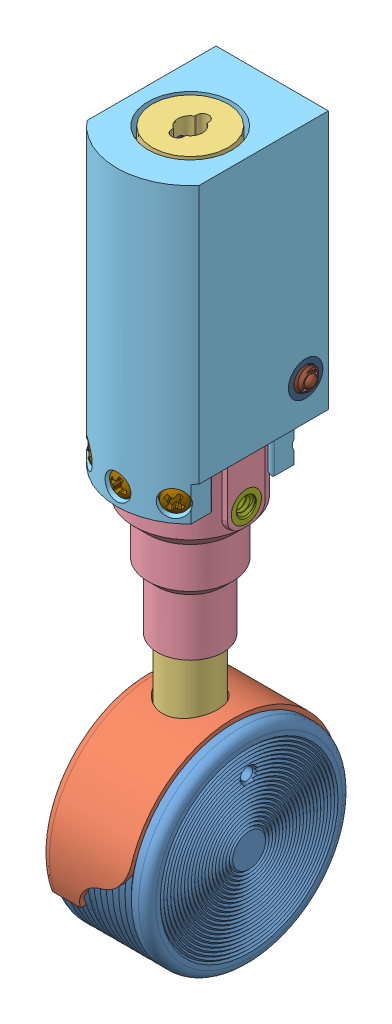
SolidWorks assembly Landing Gear Lever, configuration Default. Lengths in mm.
Overall size (23.88 129.03 39.18).
31 component instances, 15 part files, 46 mates.
Components (placement in the parent):
- Landing Gear Level Lollipop-1: Landing Gear Level Lollipop [Default] at origin size (18.84 37.59 37.59)
- Landing Gear Level Lollipop Cover-1: Landing Gear Level Lollipop Cover [Default] at origin size (15.98 27.07 39.18)
- Landing Gear Lever Shaft-1: Landing Gear Lever Shaft [Default] at (0 -43.4975 0) x (1 0 0) z (0 1 0) size (13.97 13.97 104.68)
- Landing Gear Lever Collar-1: Landing Gear Lever Collar [Default] at (0 19.05 0) x (1 0 0) z (0 1 0) size (20.7 20.7 33.34)
- Landing Gear Lever Track-1: Landing Gear Lever Track [Default] at (0 66.7385 0) x (1 0 0) z (0 1 0) size (20.7 28.64 54.09)
- 93365A110_BRASS HEAT-SET INSERT FOR PLASTICS_2-56-1: 93365A110_BRASS HEAT-SET INSERT FOR PLASTICS_2-56 [Default] at (52.1214 15.875 36.9487) x (0.77218 0.298318 -0.561021) z (0.241345 -0.954466 -0.175347) size (3.58 3.09 3.58)
- 93365A110_BRASS HEAT-SET INSERT FOR PLASTICS_2-56-2: 93365A110_BRASS HEAT-SET INSERT FOR PLASTICS_2-56 [Default] at (52.1214 15.875 20.2013) x (-0.77218 0.298318 -0.561021) z (-0.241345 -0.954466 -0.175347) size (3.58 3.09 3.58)
- 93365A110_BRASS HEAT-SET INSERT FOR PLASTICS_2-56-3: 93365A110_BRASS HEAT-SET INSERT FOR PLASTICS_2-56 [Default] at (46.0375 15.875 18.2245) x (-0.954466 0.298318 0) z (-0.298318 -0.954466 0) size (3.58 3.09 3.58)
- 93365A110_BRASS HEAT-SET INSERT FOR PLASTICS_2-56-4: 93365A110_BRASS HEAT-SET INSERT FOR PLASTICS_2-56 [Default] at (39.9536 15.875 20.2013) x (-0.77218 0.298318 0.561021) z (-0.241345 -0.954466 0.175347) size (3.58 3.09 3.58)
- 93365A110_BRASS HEAT-SET INSERT FOR PLASTICS_2-56-5: 93365A110_BRASS HEAT-SET INSERT FOR PLASTICS_2-56 [Default] at (39.9536 15.875 36.9487) x (0.77218 0.298318 0.561021) z (0.241345 -0.954466 0.175347) size (3.58 3.09 3.58)
- 93365A130 - INSERT, 6-32, BRASS, FOR PLASTICS-1: 93365A130 - INSERT, 6-32, BRASS, FOR PLASTICS [93365A130] at (35.687 11.1125 28.575) x (0 -0.259173 -0.965831) z (0 0.965831 -0.259173) size (5.56 4.29 5.56)
- 93365A130 - INSERT, 6-32, BRASS, FOR PLASTICS-2: 93365A130 - INSERT, 6-32, BRASS, FOR PLASTICS [93365A130] at (56.388 11.1125 28.575) x (0 0.666184 -0.745788) z (0 -0.745788 -0.666184) size (5.56 4.29 5.56)
- 2467A322 - PLUNGER, BALL, LONG-NOSE, 6-32-1: 2467A322 - PLUNGER, BALL, LONG-NOSE, 6-32 [2467A322] at (45.7962 61.976 28.575) x (0 -0.883555 -0.468328) z (0 0.468328 -0.883555) size (3.6 15.47 3.52)
- 93365A130 - INSERT, 6-32, BRASS, FOR PLASTICS-3: 93365A130 - INSERT, 6-32, BRASS, FOR PLASTICS [93365A130] at (39.0525 61.976 28.575) x (0 -0.827711 0.561154) z (0 -0.561154 -0.827711) size (5.56 4.29 5.56)
- 93365A130 - INSERT, 6-32, BRASS, FOR PLASTICS-4: 93365A130 - INSERT, 6-32, BRASS, FOR PLASTICS [93365A130] at (53.0225 61.976 28.575) x (0 0.992137 -0.125155) z (0 -0.125155 -0.992137) size (5.56 4.29 5.56)
- 93365A110_BRASS HEAT-SET INSERT FOR PLASTICS_2-56-6: 93365A110_BRASS HEAT-SET INSERT FOR PLASTICS_2-56 [Default] at (46.0375 15.875 38.9255) x (0.954466 0.298318 0) z (0.298318 -0.954466 0) size (3.58 3.09 3.58)
- 90272A077_ZINC-PLTD STL PAN HEAD PHILLIPS MACHINE SCREW_2-56 X .250-1: 90272A077_ZINC-PLTD STL PAN HEAD PHILLIPS MACHINE SCREW_2-56 X .250 [90272A077] at (49.3295 15.875 33.1061) x (0.466762 0.81678 -0.339122) z (0.587785 0 0.809017) size (4.24 4.24 7.94)
- 90272A077_ZINC-PLTD STL PAN HEAD PHILLIPS MACHINE SCREW_2-56 X .250-2: 90272A077_ZINC-PLTD STL PAN HEAD PHILLIPS MACHINE SCREW_2-56 X .250 [90272A077] at (42.7455 15.875 33.1061) x (0.639533 0.612454 0.464648) z (-0.587785 0 0.809017) size (4.24 4.24 7.94)
- 90272A077_ZINC-PLTD STL PAN HEAD PHILLIPS MACHINE SCREW_2-56 X .250-3: 90272A077_ZINC-PLTD STL PAN HEAD PHILLIPS MACHINE SCREW_2-56 X .250 [90272A077] at (42.7455 15.875 24.0439) x (-0.331042 -0.912449 0.240516) z (-0.587785 0 -0.809017) size (4.24 4.24 7.94)
- 90272A077_ZINC-PLTD STL PAN HEAD PHILLIPS MACHINE SCREW_2-56 X .250-4: 90272A077_ZINC-PLTD STL PAN HEAD PHILLIPS MACHINE SCREW_2-56 X .250 [90272A077] at (49.3295 15.875 24.0439) x (-0.765783 0.322529 -0.556374) z (0.587785 0 -0.809017) size (4.24 4.24 7.94)
- 90272A077_ZINC-PLTD STL PAN HEAD PHILLIPS MACHINE SCREW_2-56 X .250-5: 90272A077_ZINC-PLTD STL PAN HEAD PHILLIPS MACHINE SCREW_2-56 X .250 [90272A077] at (46.0375 15.875 34.1757) x (0.942667 -0.333735 0) z (0 0 1) size (4.24 4.24 7.94)
- 90272A077_ZINC-PLTD STL PAN HEAD PHILLIPS MACHINE SCREW_2-56 X .250-6: 90272A077_ZINC-PLTD STL PAN HEAD PHILLIPS MACHINE SCREW_2-56 X .250 [90272A077] at (46.0375 15.875 22.9743) x (-0.742719 0.669603 0) z (0 0 -1) size (4.24 4.24 7.94)
- 93365A140 - INSERT, 8-32, BRASS, FOR PLASTICS-1: 93365A140 - INSERT, 8-32, BRASS, FOR PLASTICS [93365A140] at (35.687 26.0985 17.653) x (0 0.988882 0.148702) z (0 -0.148702 0.988882) size (6.35 5.19 6.35)
- 93365A140 - INSERT, 8-32, BRASS, FOR PLASTICS-2: 93365A140 - INSERT, 8-32, BRASS, FOR PLASTICS [93365A140] at (56.388 26.0985 17.653) x (0 -0.894531 0.447005) z (0 0.447005 0.894531) size (6.35 5.19 6.35)
- 5901A122 - PLUNGER, SPRING, BALL-NOSE, 8-32 HEX DRIVE-1: 5901A122 - PLUNGER, SPRING, BALL-NOSE, 8-32 HEX DRIVE [5901A122] at (40.386 26.0985 17.653) x (0 0.998408 0.0564) z (0 -0.0564 0.998408) size (4.28 12.3 4.19)
- 5901A122 - PLUNGER, SPRING, BALL-NOSE, 8-32 HEX DRIVE-2: 5901A122 - PLUNGER, SPRING, BALL-NOSE, 8-32 HEX DRIVE [5901A122] at (51.689 26.0985 17.653) x (0 0.60561 -0.795762) z (0 -0.795762 -0.60561) size (4.28 12.3 4.19)
- 93365A102__BRASS HEAT-SET INSERT FOR PLASTICS_0-80-1: 93365A102__BRASS HEAT-SET INSERT FOR PLASTICS_0-80 [Default] at (56.388 63.5635 22.9461) x (0 -0.924225 0.381849) z (0 0.381849 0.924225) size (3.58 3.01 3.58)
- 93365A102__BRASS HEAT-SET INSERT FOR PLASTICS_0-80-2: 93365A102__BRASS HEAT-SET INSERT FOR PLASTICS_0-80 [Default] at (56.388 63.5635 16.4211) x (0 -0.85199 0.523557) z (0 0.523557 0.85199) size (3.58 3.01 3.58)
- 92671A115 - NUT, HEX, 0-80, BRASS-1: 92671A115 - NUT, HEX, 0-80, BRASS [92671A115] at (38.2984 -31.5595 28.575) x (0 -0.5 -0.866025) z (0 -0.866025 0.5) size (3.97 1.51 4.58)
- 91771A071 - FHS, 82DEG, 0-80 X .750, 18-8-1: 91771A071 - FHS, 82DEG, 0-80 X .750, 18-8 [91771A071] at (55.3967 -31.5595 28.575) x (0 0.140431 -0.99009) z (1 0 0) size (2.84 2.84 19.26)
- TLVH4200 - LED, 3mm, RED, 2.4V, 15mA, 170 DEG VIEW ANGLE, FOR BACKLIGHTING-1: TLVH4200 - LED, 3mm, RED, 2.4V, 15mA, 170 DEG VIEW ANGLE, FOR BACKLIGHTING [Default] at (46.0375 -36.1635 28.575) x (1 0 0) z (0 0 -1) size (3.33 7.5 3.5)
Mates (geometry in assembly coordinates):
- Concentric27: concentric aligned: cylinder of Landing Gear Level Lollipop-1 through (46.0375 -43.4975 28.575) axis (-1 0 0) radius 18.0023; cylinder of Landing Gear Level Lollipop Cover-1 through (46.0375 -43.4975 28.575) axis (-1 0 0) radius 18.0023
- Concentric28: concentric aligned: cylinder of Landing Gear Level Lollipop-1 through (46.0375 -28.8925 28.575) axis (0 -1 0) radius 5.08; cylinder of Landing Gear Level Lollipop Cover-1 through (46.0375 -28.8925 28.575) axis (0 -1 0) radius 5.08
- Concentric71: concentric: cone of Landing Gear Lever Collar-1 through (35.687 11.1125 28.575) axis (1 0 0); cylinder of 93365A130 - INSERT, 6-32, BRASS, FOR PLASTICS-1 through (35.687 11.1125 28.575) axis (-1 0 0) radius 2.5273
- Coincident89: coincident: plane of Landing Gear Lever Collar-1 through (35.687 19.05 0) normal (-1 0 0); plane of 93365A130 - INSERT, 6-32, BRASS, FOR PLASTICS-1 through (35.687 11.1125 28.575) normal (-1 0 0)
- Concentric70: concentric: cone of Landing Gear Lever Collar-1 through (56.388 11.1125 28.575) axis (-1 0 0); cylinder of 93365A130 - INSERT, 6-32, BRASS, FOR PLASTICS-2 through (56.388 11.1125 28.575) axis (1 0 0) radius 2.5273
- Coincident88: coincident: plane of Landing Gear Lever Collar-1 through (56.388 19.05 0) normal (1 0 0); plane of 93365A130 - INSERT, 6-32, BRASS, FOR PLASTICS-2 through (56.388 11.1125 28.575) normal (1 0 0)
- Concentric34: concentric aligned: cylinder of 2467A322 - PLUNGER, BALL, LONG-NOSE, 6-32-1 through (37.4523 61.976 28.575) axis (-1 0 0) radius 0.5715; circle of 93365A130 - INSERT, 6-32, BRASS, FOR PLASTICS-3
- Tangent15: tangent aligned: cylinder of Landing Gear Lever Shaft-1 through (46.0375 57.2135 28.575) axis (0 1 0) radius 6.985; plane of 2467A322 - PLUNGER, BALL, LONG-NOSE, 6-32-1 through (39.0525 61.976 28.575) normal (-1 0 0)
- Concentric68: concentric aligned: cylinder of Landing Gear Lever Shaft-1 through (42.8625 61.976 28.575) axis (-1 0 0) radius 1.8986; cylinder of 93365A130 - INSERT, 6-32, BRASS, FOR PLASTICS-3 through (39.0525 61.976 28.575) axis (-1 0 0) radius 2.5273
- Tangent13: tangent aligned: cylinder of Landing Gear Lever Shaft-1 through (46.0375 57.2135 28.575) axis (0 1 0) radius 6.985; plane of 93365A130 - INSERT, 6-32, BRASS, FOR PLASTICS-3 through (39.0525 61.976 28.575) normal (-1 0 0)
- Concentric69: concentric anti-aligned: cone of Landing Gear Lever Shaft-1 through (53.0225 61.976 28.575) axis (-1 0 0); cylinder of 93365A130 - INSERT, 6-32, BRASS, FOR PLASTICS-4 through (53.0225 61.976 28.575) axis (1 0 0) radius 2.5273
- Tangent14: tangent aligned: cylinder of Landing Gear Lever Shaft-1 through (46.0375 57.2135 28.575) axis (0 1 0) radius 6.985; plane of 93365A130 - INSERT, 6-32, BRASS, FOR PLASTICS-4 through (53.0225 61.976 28.575) normal (1 0 0)
- Concentric72: concentric aligned: cone of Landing Gear Lever Collar-1 through (46.0375 15.875 38.9255) axis (0 0 -1); cone of 93365A110_BRASS HEAT-SET INSERT FOR PLASTICS_2-56-6 through (46.0375 15.875 37.8155) axis (0 0 -1)
- Tangent16: tangent aligned: cylinder of Landing Gear Lever Collar-1 through (46.0375 -21.3381 28.575) axis (0 1 0) radius 10.3505; plane of 93365A110_BRASS HEAT-SET INSERT FOR PLASTICS_2-56-6 through (44.3283 15.3408 38.9255) normal (0 0 1)
- Concentric73: concentric anti-aligned: cylinder of Landing Gear Lever Track-1 through (53.9876 15.875 39.5174) axis (0.587785 0 0.809017) radius 2.3813; cylinder of 90272A077_ZINC-PLTD STL PAN HEAD PHILLIPS MACHINE SCREW_2-56 X .250-1 through (49.3295 15.875 33.1061) axis (-0.587785 0 -0.809017) radius 2.1209
- Coincident90: coincident anti-aligned: plane of Landing Gear Lever Track-1 through (53.0619 17.0942 38.2433) normal (0.587785 0 0.809017); plane of 90272A077_ZINC-PLTD STL PAN HEAD PHILLIPS MACHINE SCREW_2-56 X .250-1 through (53.0619 15.875 38.2433) normal (-0.587785 0 -0.809017)
- Concentric74: concentric anti-aligned: cylinder of Landing Gear Lever Track-1 through (38.0874 15.875 39.5174) axis (-0.587785 0 0.809017) radius 2.3813; cylinder of 90272A077_ZINC-PLTD STL PAN HEAD PHILLIPS MACHINE SCREW_2-56 X .250-2 through (42.7455 15.875 33.1061) axis (0.587785 0 -0.809017) radius 2.1209
- Coincident91: coincident anti-aligned: plane of Landing Gear Lever Track-1 through (39.0131 17.0942 38.2433) normal (-0.587785 0 0.809017); plane of 90272A077_ZINC-PLTD STL PAN HEAD PHILLIPS MACHINE SCREW_2-56 X .250-2 through (39.0131 15.875 38.2433) normal (0.587785 0 -0.809017)
- Concentric75: concentric anti-aligned: cylinder of Landing Gear Lever Track-1 through (38.0874 15.875 17.6326) axis (-0.587785 0 -0.809017) radius 2.3813; cylinder of 90272A077_ZINC-PLTD STL PAN HEAD PHILLIPS MACHINE SCREW_2-56 X .250-3 through (42.7455 15.875 24.0439) axis (0.587785 0 0.809017) radius 2.1209
- Coincident92: coincident anti-aligned: plane of Landing Gear Lever Track-1 through (39.0131 17.0942 18.9067) normal (-0.587785 0 -0.809017); plane of 90272A077_ZINC-PLTD STL PAN HEAD PHILLIPS MACHINE SCREW_2-56 X .250-3 through (39.0131 15.875 18.9067) normal (0.587785 0 0.809017)
- Concentric76: concentric anti-aligned: cylinder of Landing Gear Lever Track-1 through (53.9876 15.875 17.6326) axis (0.587785 0 -0.809017) radius 2.3813; cylinder of 90272A077_ZINC-PLTD STL PAN HEAD PHILLIPS MACHINE SCREW_2-56 X .250-4 through (49.3295 15.875 24.0439) axis (-0.587785 0 0.809017) radius 2.1209
- Coincident93: coincident anti-aligned: plane of Landing Gear Lever Track-1 through (53.0619 17.0942 18.9067) normal (0.587785 0 -0.809017); plane of 90272A077_ZINC-PLTD STL PAN HEAD PHILLIPS MACHINE SCREW_2-56 X .250-4 through (53.0619 15.875 18.9067) normal (-0.587785 0 0.809017)
- Concentric77: concentric anti-aligned: cylinder of Landing Gear Lever Track-1 through (46.0375 15.875 42.1005) axis (0 0 1) radius 2.3813; cylinder of 90272A077_ZINC-PLTD STL PAN HEAD PHILLIPS MACHINE SCREW_2-56 X .250-5 through (46.0375 15.875 34.1757) axis (0 0 -1) radius 2.1209
- Coincident94: coincident anti-aligned: plane of Landing Gear Lever Track-1 through (47.2567 15.875 40.5257) normal (0 0 1); plane of 90272A077_ZINC-PLTD STL PAN HEAD PHILLIPS MACHINE SCREW_2-56 X .250-5 through (46.0375 15.875 40.5257) normal (0 0 -1)
- Concentric78: concentric anti-aligned: cylinder of Landing Gear Lever Track-1 through (46.0375 15.875 15.0495) axis (0 0 -1) radius 2.3813; cylinder of 90272A077_ZINC-PLTD STL PAN HEAD PHILLIPS MACHINE SCREW_2-56 X .250-6 through (46.0375 15.875 22.9743) axis (0 0 1) radius 2.1209
- Coincident95: coincident anti-aligned: plane of Landing Gear Lever Track-1 through (47.2567 15.875 16.6243) normal (0 0 -1); plane of 90272A077_ZINC-PLTD STL PAN HEAD PHILLIPS MACHINE SCREW_2-56 X .250-6 through (46.0375 15.875 16.6243) normal (0 0 1)
- Concentric79: concentric anti-aligned: cone of Landing Gear Lever Track-1 through (35.687 26.0985 17.653) axis (1 0 0); cylinder of 93365A140 - INSERT, 8-32, BRASS, FOR PLASTICS-1 through (35.687 26.0985 17.653) axis (-1 0 0) radius 2.8702
- Coincident96: coincident aligned: plane of Landing Gear Lever Track-1 through (35.687 -9.5977 42.1005) normal (-1 0 0); plane of 93365A140 - INSERT, 8-32, BRASS, FOR PLASTICS-1 through (35.687 26.0985 17.653) normal (-1 0 0)
- Concentric80: concentric anti-aligned: cone of Landing Gear Lever Track-1 through (56.388 26.0985 17.653) axis (-1 0 0); cylinder of 93365A140 - INSERT, 8-32, BRASS, FOR PLASTICS-2 through (56.388 26.0985 17.653) axis (1 0 0) radius 2.8702
- Coincident97: coincident aligned: plane of Landing Gear Lever Track-1 through (56.388 -9.5977 42.1005) normal (1 0 0); plane of 93365A140 - INSERT, 8-32, BRASS, FOR PLASTICS-2 through (56.388 26.0985 17.653) normal (1 0 0)
- Concentric81: concentric aligned: cylinder of Landing Gear Lever Track-1 through (40.386 26.0985 17.653) axis (-1 0 0) radius 2.4574; circle of 5901A122 - PLUNGER, SPRING, BALL-NOSE, 8-32 HEX DRIVE-1
- Coincident98: coincident anti-aligned: plane of Landing Gear Lever Track-1 through (46.0375 66.7385 0) normal (-1 0 0); plane of 5901A122 - PLUNGER, SPRING, BALL-NOSE, 8-32 HEX DRIVE-1 through (46.0375 26.0985 17.653) normal (1 0 0)
- Concentric82: concentric anti-aligned: circle of 5901A122 - PLUNGER, SPRING, BALL-NOSE, 8-32 HEX DRIVE-1; circle of 5901A122 - PLUNGER, SPRING, BALL-NOSE, 8-32 HEX DRIVE-2
- Coincident99: coincident anti-aligned: plane of 5901A122 - PLUNGER, SPRING, BALL-NOSE, 8-32 HEX DRIVE-1 through (46.0375 26.0985 17.653) normal (1 0 0); plane of 5901A122 - PLUNGER, SPRING, BALL-NOSE, 8-32 HEX DRIVE-2 through (46.0375 26.0985 17.653) normal (-1 0 0)
- Concentric90: concentric aligned: cone of Landing Gear Lever Track-1 through (56.388 63.5635 22.9461) axis (-1 0 0); cone of 93365A102__BRASS HEAT-SET INSERT FOR PLASTICS_0-80-1 through (55.278 63.5635 22.9461) axis (-1 0 0)
- Coincident116: coincident aligned: plane of Landing Gear Lever Track-1 through (56.388 -9.5977 42.1005) normal (1 0 0); plane of 93365A102__BRASS HEAT-SET INSERT FOR PLASTICS_0-80-1 through (56.388 65.2185 22.2623) normal (1 0 0)
- Concentric91: concentric aligned: cone of Landing Gear Lever Track-1 through (56.388 63.5635 16.4211) axis (-1 0 0); cone of 93365A102__BRASS HEAT-SET INSERT FOR PLASTICS_0-80-2 through (55.278 63.5635 16.4211) axis (-1 0 0)
- Coincident117: coincident aligned: plane of Landing Gear Lever Track-1 through (56.388 -9.5977 42.1005) normal (1 0 0); plane of 93365A102__BRASS HEAT-SET INSERT FOR PLASTICS_0-80-2 through (56.388 65.0892 15.4836) normal (1 0 0)
- Concentric102: concentric aligned: cylinder of Landing Gear Level Lollipop Cover-1 through (56.896 -31.5595 28.575) axis (-1 0 0) radius 1.143; circle of 92671A115 - NUT, HEX, 0-80, BRASS-1
- Coincident128: coincident anti-aligned: plane of Landing Gear Level Lollipop Cover-1 through (38.8937 0 0) normal (-1 0 0); plane of 92671A115 - NUT, HEX, 0-80, BRASS-1 through (38.8937 -29.5751 29.7207) normal (1 0 0)
- Parallel12: parallel aligned: plane of Landing Gear Level Lollipop Cover-1 through (46.0375 -49.5935 10.795) normal (0 -1 0); plane of 92671A115 - NUT, HEX, 0-80, BRASS-1 through (38.8937 -33.5439 29.7207) normal (0 -1 0)
- Concentric103: concentric aligned: cone of Landing Gear Level Lollipop-1 through (56.896 -31.5595 28.575) axis (-1 0 0); cone of 91771A071 - FHS, 82DEG, 0-80 X .750, 18-8-1 through (56.2857 -31.5595 28.575) axis (-1 0 0)
- Coincident129: coincident aligned: cone of Landing Gear Level Lollipop-1 through (56.896 -31.5595 28.575) axis (-1 0 0); cone of 91771A071 - FHS, 82DEG, 0-80 X .750, 18-8-1 through (56.2857 -31.5595 28.575) axis (-1 0 0)
- Concentric104: concentric aligned: cylinder of Landing Gear Lever Shaft-1 through (46.0375 -37.9413 28.575) axis (0 1 0) radius 1.5; cylinder of TLVH4200 - LED, 3mm, RED, 2.4V, 15mA, 170 DEG VIEW ANGLE, FOR BACKLIGHTING-1 through (46.0375 -37.1635 28.575) axis (0 1 0) radius 1.5
- Parallel13: parallel anti-aligned: plane of Landing Gear Level Lollipop Cover-1 through (38.1 -37.1475 28.575) normal (-1 0 0); plane of TLVH4200 - LED, 3mm, RED, 2.4V, 15mA, 170 DEG VIEW ANGLE, FOR BACKLIGHTING-1 through (47.6186 -37.1635 29.325) normal (1 0 0)
- Coincident130: coincident anti-aligned: circle of Landing Gear Lever Shaft-1; plane of TLVH4200 - LED, 3mm, RED, 2.4V, 15mA, 170 DEG VIEW ANGLE, FOR BACKLIGHTING-1 through (44.2875 -36.6635 28.575) normal (0 -1 0)
